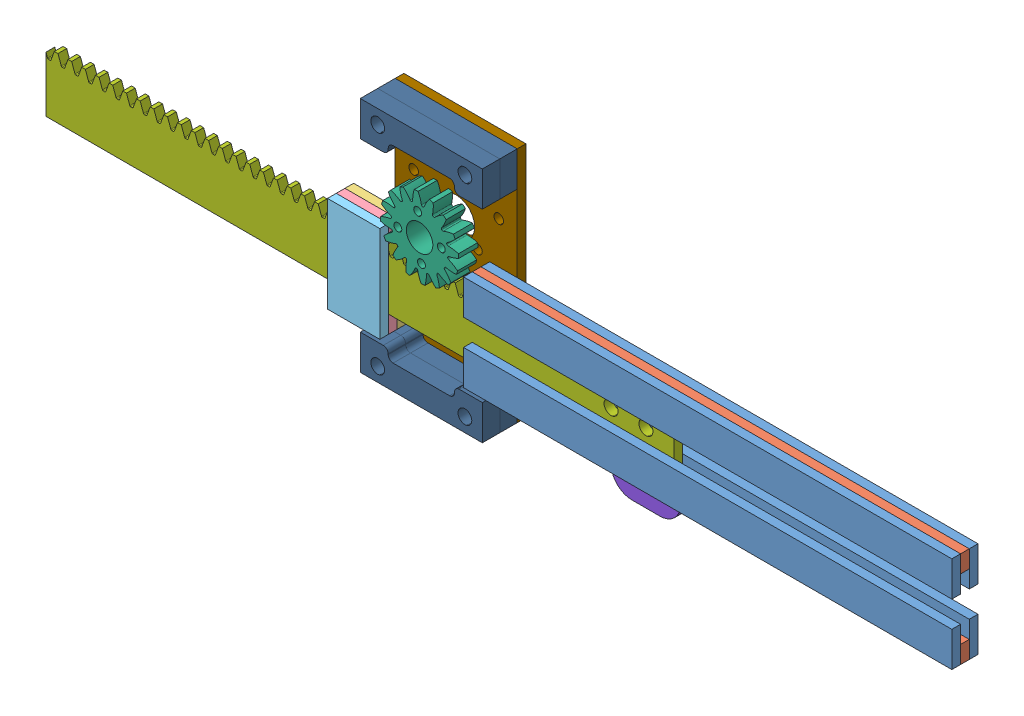
SolidWorks assembly Rack and pinion concept 1, configuration Default. Lengths in mm.
Overall size (333 86.68 16.51).
20 component instances, 11 part files, 54 mates.
Components (placement in the parent):
- edge 1-1: edge 1 [Default] at (-18.8583 14.1907 -1.2772) size (177.8 12.7 3.17)
- edge 1-2: edge 1 [Default] at (-18.8583 -8.0343 -1.2772) size (177.8 12.7 3.17)
- small edge^Rack and pinion concept 1-1: small edge^Rack and pinion concept 1 [Default] at (11.5293 5.8905 1.8978) size (177.8 6.35 3.17) (virtual)
- small edge^Rack and pinion concept 1-2: small edge^Rack and pinion concept 1 [Default] at (-49.2458 0.266 1.8978) x (-1 0 0) z (0 0 1) size (177.8 6.35 3.17) (virtual)
- edge 1-3: edge 1 [Default] at (-18.8583 -8.0343 5.0728) size (177.8 12.7 3.17)
- edge 1-4: edge 1 [Default] at (-18.8583 14.1907 5.0728) x (-1 0 0) z (0 0 1) size (177.8 12.7 3.17)
- Part4^Rack and pinion concept 1-1: Part4^Rack and pinion concept 1 [Default] at (-49.2946 -71.7741 -1.2772) size (19.05 12.7 3.17) (virtual)
- Part4^Rack and pinion concept 1-2: Part4^Rack and pinion concept 1 [Default] at (-246.232 77.9306 -1.2772) x (-1 0 0) z (0 0 1) size (19.05 12.7 3.17) (virtual)
- Part5^Rack and pinion concept 1-1: Part5^Rack and pinion concept 1 [Default] at origin (virtual)
- Part6^Rack and pinion concept 1-1: Part6^Rack and pinion concept 1 [Default] at (-76.9681 -44.0224 1.8978) size (19.05 6.35 3.17) (virtual)
- Part6^Rack and pinion concept 1-2: Part6^Rack and pinion concept 1 [Default] at (-76.9681 50.1788 5.0728) x (1 0 0) z (0 0 -1) size (19.05 6.35 3.17) (virtual)
- Part7^Rack and pinion concept 1-1: Part7^Rack and pinion concept 1 [Default] at (6.1505 -10.9425 5.0728) size (19.05 34.92 3.17) (virtual)
- 5172T630_METAL GEAR - 20 DEGREE PRESSURE ANGLE-1: 5172T630_METAL GEAR - 20 DEGREE PRESSURE ANGLE [5172T63] at (-123.1253 25.6057 18.4078) x (0.876843 -0.480777 0) z (0 0 -1) size (28.27 28.27 6.99)
- 5174T200_HT-LOAD MTL GEAR RACK--20 DEG PRESSURE ANGLE-1: 5174T200_HT-LOAD MTL GEAR RACK--20 DEG PRESSURE ANGLE [5174T2] at (-339.1545 4.4371 -4.4522) size (228.6 22 3.18)
- Деталь1^Rack and pinion concept 1-1: Деталь1^Rack and pinion concept 1 [По умолчанию] at (-164.5325 -85.8188 -4.4522) size (25.4 38.1 3.17) (virtual)
- Деталь2^Rack and pinion concept 1-1: Деталь2^Rack and pinion concept 1 [По умолчанию] at (-18.6541 -20.4785 -7.6272) size (44.45 86.36 3.17) (virtual)
- Деталь3^Rack and pinion concept 1-1: Деталь3^Rack and pinion concept 1 [По умолчанию] at (1.4535 0 -4.4522) size (44.45 12.7 6.35) (virtual)
- Деталь3^Rack and pinion concept 1-2: Деталь3^Rack and pinion concept 1 [По умолчанию] at (1.4535 0 1.8978) size (44.45 12.7 6.35) (virtual)
- Деталь3^Rack and pinion concept 1-4: Деталь3^Rack and pinion concept 1 [По умолчанию] at (-247.7041 29.6515 -4.4522) x (-1 0 0) z (0 0 1) size (44.45 12.7 6.35) (virtual)
- Деталь3^Rack and pinion concept 1-6: Деталь3^Rack and pinion concept 1 [По умолчанию] at (-247.7041 29.6515 1.8978) x (-1 0 0) z (0 0 1) size (44.45 12.7 6.35) (virtual)
Mates (geometry in assembly coordinates):
- Coincident1: coincident aligned: plane of edge 1-1 through (-18.8583 14.1907 -1.2772) normal (0 0 -1); plane of edge 1-2 through (-18.8583 -8.0343 -1.2772) normal (0 0 -1)
- Coincident2: coincident aligned: plane of edge 1-1 through (70.0417 7.8407 1.8978) normal (1 0 0); plane of edge 1-2 through (70.0417 -14.3843 1.8978) normal (1 0 0)
- Distance1: distance = 9.525 mm anti-aligned: plane of edge 1-1 through (-107.7583 7.8407 1.8978) normal (0 -1 0); plane of edge 1-2 through (-107.7583 -1.6843 1.8978) normal (0 1 0)
- Coincident4: coincident anti-aligned: plane of edge 1-1 through (-18.8583 14.1907 1.8978) normal (0 0 1); plane of Part2^Rack and pinion concept 1-1 through (11.5293 5.8905 1.8978) normal (0 0 -1)
- Coincident5: coincident aligned: plane of edge 1-1 through (-107.7583 20.5407 1.8978) normal (0 1 0); plane of Part2^Rack and pinion concept 1-1 through (-107.7583 20.5407 5.0728) normal (0 1 0)
- Coincident6: coincident aligned: plane of edge 1-1 through (70.0417 7.8407 1.8978) normal (1 0 0); plane of Part2^Rack and pinion concept 1-1 through (70.0417 14.1907 5.0728) normal (1 0 0)
- Coincident7: coincident anti-aligned: plane of edge 1-2 through (-18.8583 -8.0343 1.8978) normal (0 0 1); plane of Part2^Rack and pinion concept 1-2 through (-49.2458 0.266 1.8978) normal (0 0 -1)
- Coincident8: coincident aligned: plane of edge 1-2 through (-107.7583 -14.3843 1.8978) normal (0 -1 0); plane of Part2^Rack and pinion concept 1-2 through (70.0417 -14.3843 5.0728) normal (0 -1 0)
- Coincident10: coincident aligned: plane of edge 1-2 through (-107.7583 -14.3843 1.8978) normal (-1 0 0); plane of Part2^Rack and pinion concept 1-2 through (-107.7583 -8.0343 5.0728) normal (-1 0 0)
- Coincident11: coincident anti-aligned: plane of Part2^Rack and pinion concept 1-2 through (-49.2458 0.266 5.0728) normal (0 0 1); plane of edge 1-3 through (-18.8583 -8.0343 5.0728) normal (0 0 -1)
- Coincident12: coincident aligned: plane of Part2^Rack and pinion concept 1-2 through (70.0417 -8.0343 5.0728) normal (1 0 0); plane of edge 1-3 through (70.0417 -14.3843 8.2478) normal (1 0 0)
- Coincident13: coincident aligned: plane of Part2^Rack and pinion concept 1-2 through (70.0417 -14.3843 5.0728) normal (0 -1 0); plane of edge 1-3 through (-107.7583 -14.3843 8.2478) normal (0 -1 0)
- Coincident14: coincident anti-aligned: plane of Part2^Rack and pinion concept 1-1 through (11.5293 5.8905 5.0728) normal (0 0 1); plane of edge 1-4 through (-18.8583 14.1907 5.0728) normal (0 0 -1)
- Coincident16: coincident aligned: plane of Part2^Rack and pinion concept 1-1 through (-107.7583 20.5407 5.0728) normal (0 1 0); plane of edge 1-4 through (70.0417 20.5407 8.2478) normal (0 1 0)
- Coincident17: coincident aligned: plane of Part2^Rack and pinion concept 1-1 through (-107.7583 14.1907 5.0728) normal (-1 0 0); plane of edge 1-4 through (-107.7583 20.5407 8.2478) normal (-1 0 0)
- Coincident22: coincident aligned: plane of edge 1-1 through (-107.7583 20.5407 1.8978) normal (0 1 0); plane of Part4^Rack and pinion concept 1-1 through (-157.2883 20.5407 1.8978) normal (0 1 0)
- Coincident23: coincident aligned: plane of edge 1-1 through (-18.8583 14.1907 -1.2772) normal (0 0 -1); plane of Part4^Rack and pinion concept 1-1 through (-49.2946 -71.7741 -1.2772) normal (0 0 -1)
- Distance2: distance = 30.48 mm anti-aligned: plane of Part4^Rack and pinion concept 1-1 through (-138.2383 20.5407 1.8978) normal (1 0 0); plane of edge 1-1 through (-107.7583 7.8407 1.8978) normal (-1 0 0)
- Coincident25: coincident aligned: plane of edge 1-2 through (-107.7583 -14.3843 1.8978) normal (0 -1 0); plane of Part4^Rack and pinion concept 1-2 through (-138.2383 -14.3843 1.8978) normal (0 -1 0)
- Coincident26: coincident aligned: plane of edge 1-2 through (-18.8583 -8.0343 -1.2772) normal (0 0 -1); plane of Part4^Rack and pinion concept 1-2 through (-246.232 77.9306 -1.2772) normal (0 0 -1)
- Distance4: distance = 30.48 mm anti-aligned: plane of edge 1-2 through (-107.7583 -14.3843 1.8978) normal (-1 0 0); plane of Part4^Rack and pinion concept 1-2 through (-138.2383 -14.3843 1.8978) normal (1 0 0)
- Coincident27: coincident aligned: plane of Part4^Rack and pinion concept 1-1 through (-157.2883 20.5407 1.8978) normal (-1 0 0); plane of Part6^Rack and pinion concept 1-1 through (-157.2883 20.5407 5.0728) normal (-1 0 0)
- Coincident28: coincident anti-aligned: plane of Part4^Rack and pinion concept 1-1 through (-49.2946 -71.7741 1.8978) normal (0 0 1); plane of Part6^Rack and pinion concept 1-1 through (-76.9681 -44.0224 1.8978) normal (0 0 -1)
- Coincident29: coincident aligned: plane of Part4^Rack and pinion concept 1-1 through (-157.2883 20.5407 1.8978) normal (0 1 0); plane of Part6^Rack and pinion concept 1-1 through (-157.2883 20.5407 5.0728) normal (0 1 0)
- Coincident30: coincident aligned: plane of Part4^Rack and pinion concept 1-2 through (-157.2883 -14.3843 1.8978) normal (-1 0 0); plane of Part6^Rack and pinion concept 1-2 through (-157.2883 -14.3843 1.8978) normal (-1 0 0)
- Coincident32: coincident aligned: plane of Part4^Rack and pinion concept 1-2 through (-138.2383 -14.3843 1.8978) normal (0 -1 0); plane of Part6^Rack and pinion concept 1-2 through (-157.2883 -14.3843 1.8978) normal (0 -1 0)
- Coincident35: coincident anti-aligned: plane of Part4^Rack and pinion concept 1-2 through (-246.232 77.9306 1.8978) normal (0 0 1); plane of Part6^Rack and pinion concept 1-2 through (-76.9681 50.1788 1.8978) normal (0 0 -1)
- Coincident36: coincident anti-aligned: plane of Part6^Rack and pinion concept 1-1 through (-76.9681 -44.0224 5.0728) normal (0 0 1); plane of Part7^Rack and pinion concept 1-1 through (6.1505 -10.9425 5.0728) normal (0 0 -1)
- Coincident37: coincident aligned: plane of Part6^Rack and pinion concept 1-1 through (-157.2883 20.5407 5.0728) normal (-1 0 0); plane of Part7^Rack and pinion concept 1-1 through (-157.2883 20.5407 8.2478) normal (-1 0 0)
- Coincident38: coincident aligned: plane of Part6^Rack and pinion concept 1-1 through (-157.2883 20.5407 5.0728) normal (0 1 0); plane of Part7^Rack and pinion concept 1-1 through (-157.2883 20.5407 8.2478) normal (0 1 0)
- Coincident42: coincident anti-aligned: plane of edge 1-1 through (-18.8583 14.1907 1.8978) normal (0 0 1); plane of 5172T630_METAL GEAR - 20 DEGREE PRESSURE ANGLE-1 through (-123.1253 25.6057 1.8978) normal (0 0 -1)
- Coincident43: coincident anti-aligned: plane of edge 1-2 through (-18.8583 -8.0343 1.8978) normal (0 0 1); plane of 5174T200_HT-LOAD MTL GEAR RACK--20 DEG PRESSURE ANGLE-1 through (-339.1545 4.4371 1.8978) normal (0 0 -1)
- Coincident44: coincident anti-aligned: plane of small edge^Rack and pinion concept 1-2 through (70.0417 -8.0343 5.0728) normal (0 1 0); plane of 5174T200_HT-LOAD MTL GEAR RACK--20 DEG PRESSURE ANGLE-1 through (-339.1545 -8.0343 -4.4522) normal (0 -1 0)
- RackPinionMate1: rack pinion = 25.4 mm: line of 5174T200_HT-LOAD MTL GEAR RACK--20 DEG PRESSURE ANGLE-1 through (-262.9545 -8.0343 1.8978) axis (1 0 0); circle of 5172T630_METAL GEAR - 20 DEGREE PRESSURE ANGLE-1
- Совпадение2: coincident anti-aligned: plane of edge 1-2 through (-18.8583 -8.0343 -1.2772) normal (0 0 -1); plane of Деталь1^Rack and pinion concept 1-1 through (-55.9445 -21.0518 -1.2772) normal (0 0 1)
- Концентричный1: concentric aligned: cylinder of 5174T200_HT-LOAD MTL GEAR RACK--20 DEG PRESSURE ANGLE-1 through (-57.2145 3.0782 1.8978) axis (0 0 -1) radius 2.5527; cylinder of Деталь1^Rack and pinion concept 1-1 through (-57.2145 3.0782 -4.4522) axis (0 0 -1) radius 2.5527
- Концентричный2: concentric aligned: cylinder of 5174T200_HT-LOAD MTL GEAR RACK--20 DEG PRESSURE ANGLE-1 through (-44.5145 3.0782 1.8978) axis (0 0 -1) radius 2.5527; cylinder of Деталь1^Rack and pinion concept 1-1 through (-44.5145 3.0782 -4.4522) axis (0 0 -1) radius 2.5527
- Параллельность1: parallel anti-aligned: plane of edge 1-1 through (-18.8583 14.1907 -1.2772) normal (0 0 -1); plane of Деталь2^Rack and pinion concept 1-1 through (-18.6541 -20.4785 -4.4522) normal (0 0 1)
- Расстояние2: distance = 11.938 mm aligned: plane of Деталь2^Rack and pinion concept 1-1 through (-145.3503 7.2057 -4.4522) normal (-1 0 0); plane of Part4^Rack and pinion concept 1-1 through (-157.2883 20.5407 1.8978) normal (-1 0 0)
- Концентричный3: concentric anti-aligned: circle of 5172T630_METAL GEAR - 20 DEGREE PRESSURE ANGLE-1; cylinder of Деталь2^Rack and pinion concept 1-1 through (-123.1253 25.6057 -4.4522) axis (0 0 -1) radius 6.75
- Совпадение15: coincident aligned: plane of Деталь2^Rack and pinion concept 1-1 through (-100.9003 58.0057 -4.4522) normal (0 1 0); plane of Деталь3^Rack and pinion concept 1-1 through (-100.9003 58.0057 1.8978) normal (0 1 0)
- Совпадение16: coincident aligned: plane of Деталь2^Rack and pinion concept 1-1 through (-145.3503 7.2057 -4.4522) normal (-1 0 0); plane of Деталь3^Rack and pinion concept 1-1 through (-145.3503 58.0057 1.8978) normal (-1 0 0)
- Совпадение17: coincident anti-aligned: plane of Деталь2^Rack and pinion concept 1-1 through (-18.6541 -20.4785 -4.4522) normal (0 0 1); plane of Деталь3^Rack and pinion concept 1-1 through (-136.9683 47.0837 -4.4522) normal (0 0 -1)
- Совпадение18: coincident aligned: plane of Деталь2^Rack and pinion concept 1-1 through (-100.9003 58.0057 -4.4522) normal (0 1 0); plane of Деталь3^Rack and pinion concept 1-2 through (-100.9003 58.0057 8.2478) normal (0 1 0)
- Совпадение19: coincident aligned: plane of Деталь2^Rack and pinion concept 1-1 through (-145.3503 7.2057 -4.4522) normal (-1 0 0); plane of Деталь3^Rack and pinion concept 1-2 through (-145.3503 58.0057 8.2478) normal (-1 0 0)
- Совпадение20: coincident anti-aligned: plane of Деталь3^Rack and pinion concept 1-1 through (-136.9683 47.0837 1.8978) normal (0 0 1); plane of Деталь3^Rack and pinion concept 1-2 through (-136.9683 47.0837 1.8978) normal (0 0 -1)
- Совпадение24: coincident aligned: plane of Деталь2^Rack and pinion concept 1-1 through (-100.9003 -28.3543 -4.4522) normal (0 -1 0); plane of Деталь3^Rack and pinion concept 1-4 through (-145.3503 -28.3543 1.8978) normal (0 -1 0)
- Совпадение26: coincident anti-aligned: plane of Деталь2^Rack and pinion concept 1-1 through (-18.6541 -20.4785 -4.4522) normal (0 0 1); plane of Деталь3^Rack and pinion concept 1-4 through (-109.2823 -17.4323 -4.4522) normal (0 0 -1)
- Совпадение27: coincident aligned: plane of Деталь2^Rack and pinion concept 1-1 through (-100.9003 7.2057 -4.4522) normal (1 0 0); plane of Деталь3^Rack and pinion concept 1-4 through (-100.9003 -28.3543 1.8978) normal (1 0 0)
- Совпадение28: coincident aligned: plane of Деталь3^Rack and pinion concept 1-4 through (-145.3503 -28.3543 1.8978) normal (0 -1 0); plane of Деталь3^Rack and pinion concept 1-6 through (-145.3503 -28.3543 8.2478) normal (0 -1 0)
- Совпадение29: coincident aligned: plane of Деталь3^Rack and pinion concept 1-4 through (-100.9003 -28.3543 1.8978) normal (1 0 0); plane of Деталь3^Rack and pinion concept 1-6 through (-100.9003 -28.3543 8.2478) normal (1 0 0)
- Совпадение30: coincident anti-aligned: plane of Деталь3^Rack and pinion concept 1-4 through (-109.2823 -17.4323 1.8978) normal (0 0 1); plane of Деталь3^Rack and pinion concept 1-6 through (-109.2823 -17.4323 1.8978) normal (0 0 -1)
- Совпадение31: coincident aligned: plane of Part7^Rack and pinion concept 1-1 through (6.1505 -10.9425 8.2478) normal (0 0 1); plane of Деталь3^Rack and pinion concept 1-6 through (-109.2823 -17.4323 8.2478) normal (0 0 1)
- Расстояние7: distance = 37.465 mm aligned: plane of Деталь2^Rack and pinion concept 1-1 through (-100.9003 58.0057 -4.4522) normal (0 1 0); plane of edge 1-1 through (-107.7583 20.5407 1.8978) normal (0 1 0)
